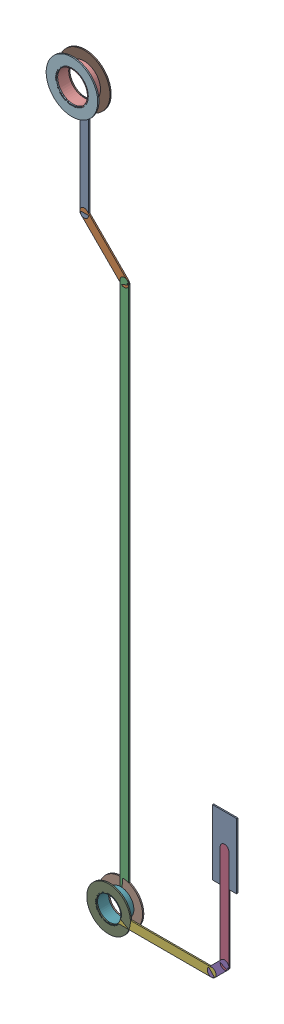
SolidWorks assembly SWCLK, configuration Predeterminado. Lengths in mm.
Overall size (5.54 21.57 0.39).
35 component instances, 11 part files, 0 mates.
Components (placement in the parent):
- Track (18.034mm,45.033mm)(18.034mm,48.387mm) on Bottom Layer-1: Track (18.034mm,45.033mm)(18.034mm,48.387mm) on Bottom Layer [Predeterminado] at origin size (0.25 3.05 0.04)
  - Track (18.034mm,45.033mm)(18.034mm,48.387mm) on Bottom Layer-1-1: Track (18.034mm,45.033mm)(18.034mm,48.387mm) on Bottom Layer-1 [Predeterminado] at (-68.317 -44.187 -0.4013) size (0.25 3.05 0.04)
    - Track (18.034mm,45.033mm)(18.034mm,48.387mm) on Bottom Layer-Part-1-1: Track (18.034mm,45.033mm)(18.034mm,48.387mm) on Bottom Layer-Part-1 [Predeterminado] at origin size (0.25 3.05 0.04)
- Track (18.034mm,45.033mm)(19.202mm,43.865mm) on Bottom Layer-1: Track (18.034mm,45.033mm)(19.202mm,43.865mm) on Bottom Layer [Predeterminado] at origin size (1.42 1.42 0.04)
  - Track (18.034mm,45.033mm)(19.202mm,43.865mm) on Bottom Layer-1-1: Track (18.034mm,45.033mm)(19.202mm,43.865mm) on Bottom Layer-1 [Predeterminado] at (-68.317 -44.187 -0.4013) size (1.42 1.42 0.04)
    - Track (18.034mm,45.033mm)(19.202mm,43.865mm) on Bottom Layer-Part-1-1: Track (18.034mm,45.033mm)(19.202mm,43.865mm) on Bottom Layer-Part-1 [Predeterminado] at origin size (1.42 1.42 0.04)
- Track (19.202mm,28.302mm)(19.202mm,43.865mm) on Bottom Layer-1: Track (19.202mm,28.302mm)(19.202mm,43.865mm) on Bottom Layer [Predeterminado] at origin size (0.25 15.52 0.04)
  - Track (19.202mm,28.302mm)(19.202mm,43.865mm) on Bottom Layer-1-1: Track (19.202mm,28.302mm)(19.202mm,43.865mm) on Bottom Layer-1 [Predeterminado] at (-68.317 -44.187 -0.4013) size (0.25 15.52 0.04)
    - Track (19.202mm,28.302mm)(19.202mm,43.865mm) on Bottom Layer-Part-1-1: Track (19.202mm,28.302mm)(19.202mm,43.865mm) on Bottom Layer-Part-1 [Predeterminado] at origin size (0.25 15.52 0.04)
- Track (22.475mm,28.475mm)(22.475mm,31.391mm) on Top Layer-1: Track (22.475mm,28.475mm)(22.475mm,31.391mm) on Top Layer [Predeterminado] at origin size (0.25 3.17 0.04)
  - Track (22.475mm,28.475mm)(22.475mm,31.391mm) on Top Layer-1-1: Track (22.475mm,28.475mm)(22.475mm,31.391mm) on Top Layer-1 [Predeterminado] at (-68.317 -44.187 -0.0457) size (0.25 3.17 0.04)
    - Track (22.475mm,28.475mm)(22.475mm,31.391mm) on Top Layer-Part-1-1: Track (22.475mm,28.475mm)(22.475mm,31.391mm) on Top Layer-Part-1 [Predeterminado] at origin size (0.25 3.17 0.04)
- Track (22.1mm,28.1mm)(22.475mm,28.475mm) on Top Layer-1: Track (22.1mm,28.1mm)(22.475mm,28.475mm) on Top Layer [Predeterminado] at origin size (0.63 0.63 0.04)
  - Track (22.1mm,28.1mm)(22.475mm,28.475mm) on Top Layer-1-1: Track (22.1mm,28.1mm)(22.475mm,28.475mm) on Top Layer-1 [Predeterminado] at (-68.317 -44.187 -0.0457) size (0.63 0.63 0.04)
    - Track (22.1mm,28.1mm)(22.475mm,28.475mm) on Top Layer-Part-1-1: Track (22.1mm,28.1mm)(22.475mm,28.475mm) on Top Layer-Part-1 [Predeterminado] at origin size (0.63 0.63 0.04)
- Track (19.2mm,28.1mm)(22.1mm,28.1mm) on Top Layer-1: Track (19.2mm,28.1mm)(22.1mm,28.1mm) on Top Layer [Predeterminado] at origin size (2.85 0.25 0.04)
  - Track (19.2mm,28.1mm)(22.1mm,28.1mm) on Top Layer-1-1: Track (19.2mm,28.1mm)(22.1mm,28.1mm) on Top Layer-1 [Predeterminado] at (-68.317 -44.187 -0.0457) size (2.85 0.25 0.04)
    - Track (19.2mm,28.1mm)(22.1mm,28.1mm) on Top Layer-Part-1-1: Track (19.2mm,28.1mm)(22.1mm,28.1mm) on Top Layer-Part-1 [Predeterminado] at origin size (2.85 0.25 0.04)
- Via (19.1mm,28.2mm) from Top Layer to Bottom Layer-1: Via (19.1mm,28.2mm) from Top Layer to Bottom Layer [Predeterminado] at origin size (1.27 1.27 0.39)
  - Via Hole-1: Via Hole [Predeterminado] at (19.1 28.2 -0.4013) size (0.76 0.76 0.39)
    - Via Hole-Part-1-1: Via Hole-Part-1 [Predeterminado] at origin size (0.76 0.76 0.39)
  - Via Top Layer-1: Via Top Layer [Predeterminado] at (19.1 28.2 -0.4013) size (1.27 1.27 0.04)
    - Via Top Layer-Part-1-1: Via Top Layer-Part-1 [Predeterminado] at origin size (1.27 1.27 0.04)
  - Via Top Layer-2: Via Top Layer [Predeterminado] at (19.1 28.2 -0.0457) size (1.27 1.27 0.04)
    - Via Top Layer-Part-1-1: Via Top Layer-Part-1 [Predeterminado] at origin size (1.27 1.27 0.04)
- Pad SWD-3(18.034mm,48.387mm) on Multi-Layer-1: Pad SWD-3(18.034mm,48.387mm) on Multi-Layer [Predeterminado] at origin size (1.5 1.5 0.39)
  - Pad Hole-1-1: Pad Hole-1 [Predeterminado] at (18.034 48.387 -0.4013) size (0.95 0.95 0.39)
    - Pad Hole-Part-1-1-1: Pad Hole-Part-1-1 [Predeterminado] at origin size (0.95 0.95 0.39)
  - Top Layer-1-1: Top Layer-1 [Predeterminado] at (18.034 48.387 -0.4013) size (1.5 1.5 0.04)
    - Top Layer-Part-1-1-1: Top Layer-Part-1-1 [Predeterminado] at origin size (1.5 1.5 0.04)
  - Top Layer-1-2: Top Layer-1 [Predeterminado] at (18.034 48.387 -0.0457) size (1.5 1.5 0.04)
    - Top Layer-Part-1-1-1: Top Layer-Part-1-1 [Predeterminado] at origin size (1.5 1.5 0.04)
- Pad RAK4600-38(22.475mm,31.391mm) on Top Layer-1: Pad RAK4600-38(22.475mm,31.391mm) on Top Layer [Predeterminado] at origin size (0.7 1.9 0.04)
  - Pad RAK4600-38(22.475mm,31.391mm) on Top Layer-1-1: Pad RAK4600-38(22.475mm,31.391mm) on Top Layer-1 [Predeterminado] at (-68.317 -44.187 -0.0457) size (0.7 1.9 0.04)
    - Pad RAK4600-38(22.475mm,31.391mm) on Top Layer-Part-1-1: Pad RAK4600-38(22.475mm,31.391mm) on Top Layer-Part-1 [Predeterminado] at origin size (0.7 1.9 0.04)
